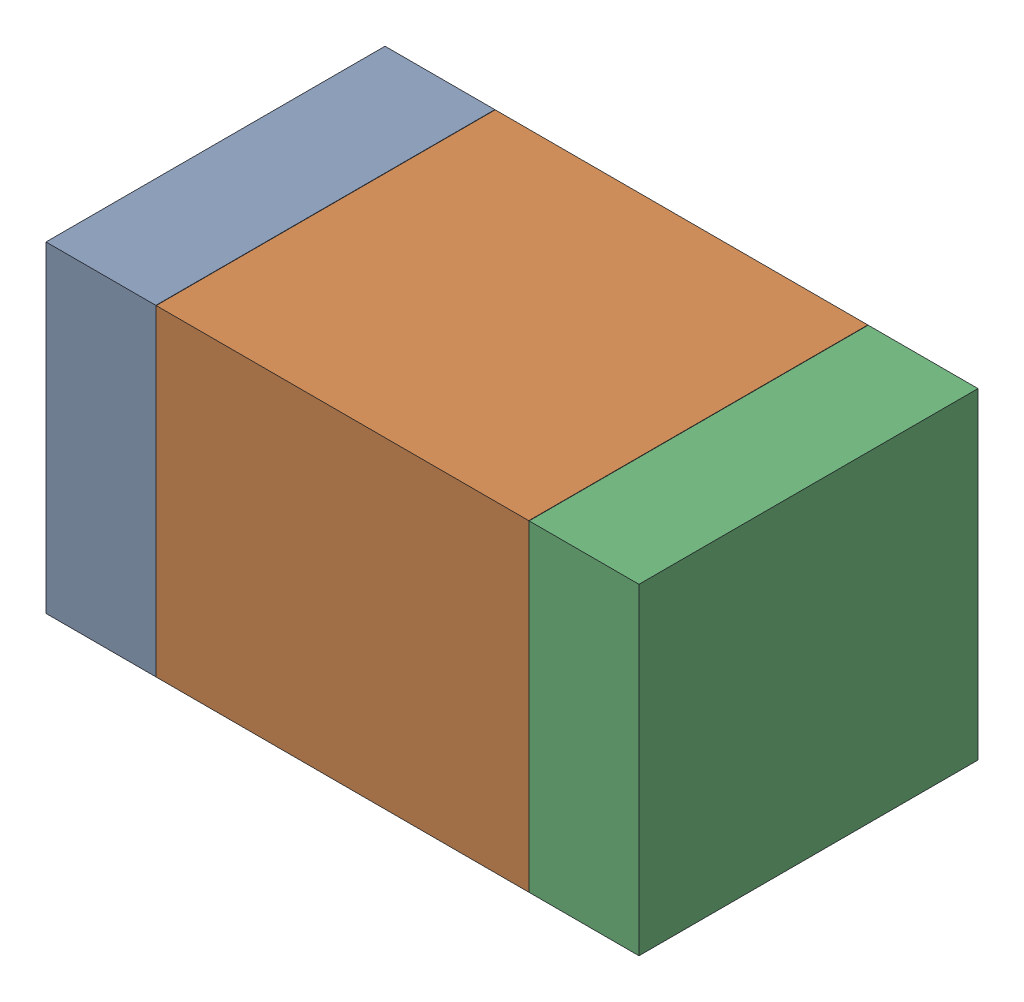
SolidWorks assembly R41, configuration Default. Lengths in mm.
Overall size (1.75 0.95 1).
6 component instances, 2 part files, 0 mates.
Components (placement in the parent):
- 6575498272-1: 6575498272 [Default] at (44.4995 12.192 0) size (0.32 0.95 1)
  - Extruded_8-1: Extruded_8 [Default] at origin size (0.32 0.95 1)
- 6575498112-1: 6575498112 [Default] at (45.212 12.192 0) size (1.1 0.95 1)
  - Extruded_9-1: Extruded_9 [Default] at origin size (1.1 0.95 1)
- 6575498272-2: 6575498272 [Default] at (45.9245 12.192 0) size (0.32 0.95 1)
  - Extruded_8-1: Extruded_8 [Default] at origin size (0.32 0.95 1)
